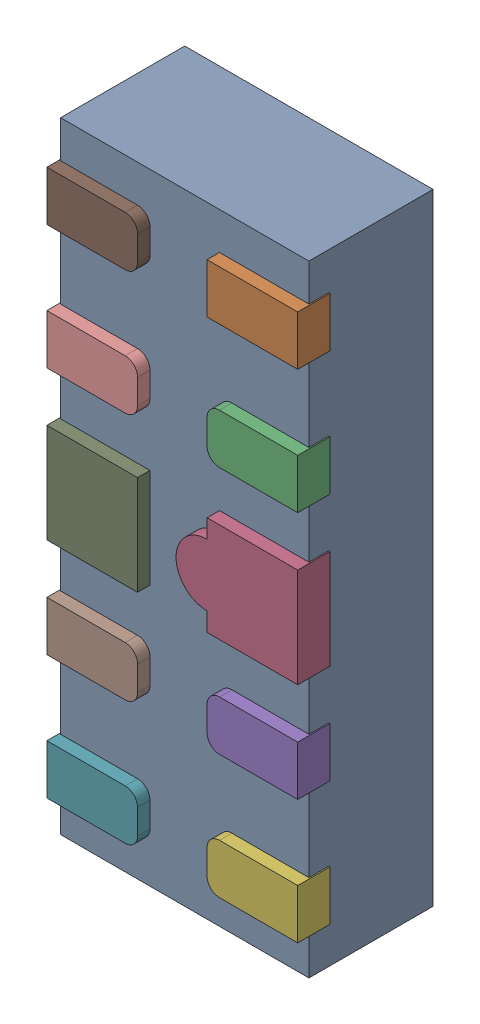
SolidWorks assembly D23, configuration Défaut. Lengths in mm.
Overall size (1.01 2.5 0.55).
12 component instances, 5 part files, 0 mates.
Components (placement in the parent):
- UDFN10-1: UDFN10 [Défaut] at (73.6831 -25.058 -1.1719) x (0 -1 0) z (1 0 0) size (2.5 0.55 1.01)
  - User Library-UDFN10_Body-1: User Library-UDFN10_Body [Défaut] at (1.0785 0.9721 1.8983) size (2.5 0.5 1)
  - User Library-UDFN10_Pin1-1: User Library-UDFN10_Pin1 [Défaut] at (0.0785 1.0521 2.2208) x (0 0 -1) z (-1 0 0) size (0.37 0.13 0.2)
  - User Library-UDFN10_Pin2-1: User Library-UDFN10_Pin2 [Défaut] at (0.5785 1.0521 2.2208) x (0 0 1) z (1 0 0) size (0.37 0.13 0.2)
  - User Library-UDFN10_Pin4-1: User Library-UDFN10_Pin4 [Défaut] at (1.0785 0.9221 2.2208) x (0 0 1) z (-1 0 0) size (0.49 0.13 0.4)
  - User Library-UDFN10_Pin2-2: User Library-UDFN10_Pin2 [Défaut] at (1.5785 0.9221 2.2208) x (0 0 1) z (-1 0 0) size (0.37 0.13 0.2)
  - User Library-UDFN10_Pin2-3: User Library-UDFN10_Pin2 [Défaut] at (2.0785 0.9221 2.2208) x (0 0 1) z (-1 0 0) size (0.37 0.13 0.2)
  - User Library-UDFN10_Pin2-4: User Library-UDFN10_Pin2 [Défaut] at (2.0785 0.9221 1.5758) x (0 0 -1) z (1 0 0) size (0.37 0.13 0.2)
  - User Library-UDFN10_Pin2-5: User Library-UDFN10_Pin2 [Défaut] at (1.5785 0.9221 1.5758) x (0 0 -1) z (1 0 0) size (0.37 0.13 0.2)
  - User Library-UDFN10_Pin3-1: User Library-UDFN10_Pin3 [Défaut] at (1.0785 0.9221 1.5758) x (0 0 1) z (-1 0 0) size (0.37 0.13 0.4)
  - User Library-UDFN10_Pin2-6: User Library-UDFN10_Pin2 [Défaut] at (0.5785 0.9221 1.5758) x (0 0 -1) z (1 0 0) size (0.37 0.13 0.2)
  - User Library-UDFN10_Pin2-7: User Library-UDFN10_Pin2 [Défaut] at (0.0785 0.9221 1.5758) x (0 0 -1) z (1 0 0) size (0.37 0.13 0.2)
